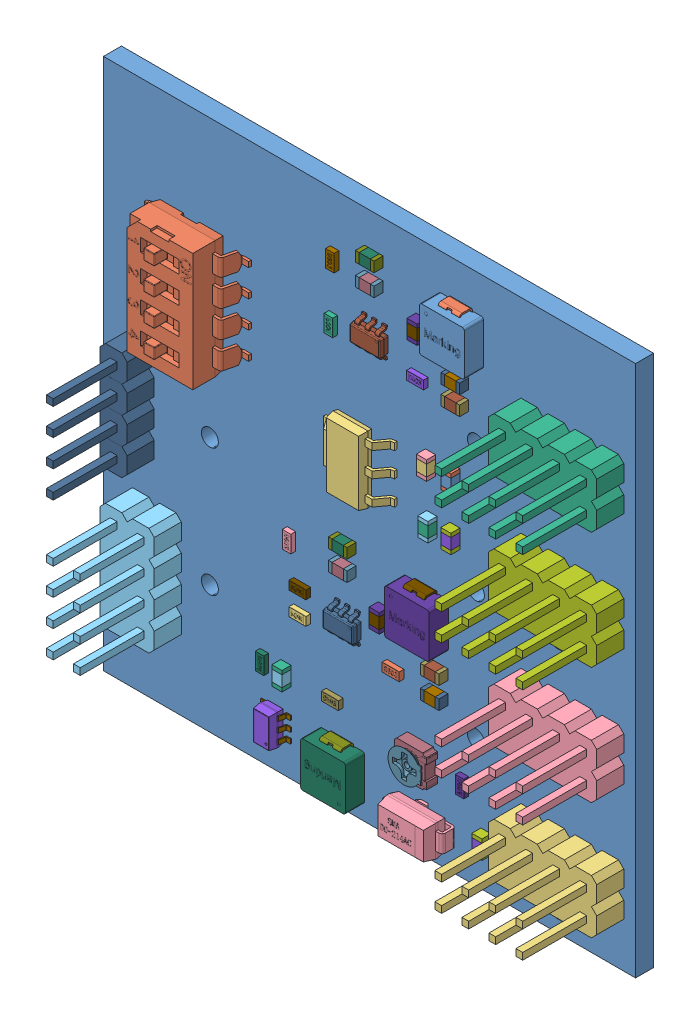
SolidWorks assembly PCB1, configuration 默认. Lengths in mm.
Overall size (50 50 11.54).
196 component instances, 72 part files, 0 mates.
Components (placement in the parent):
- PCB1(2)^PCB1-1: PCB1(2)^PCB1 [默认] at origin size (50 50 11.54) (virtual)
  - Boardbat^PCB1(2)_PCB1-1: Boardbat^PCB1(2)_PCB1 [默认] at origin size (50 50 1.69) (virtual)
    - Open CASCADE STEP translator 6.8 2.1.1^Boardbat_PCB1(2)_PCB1-1: Open CASCADE STEP translator 6.8 2.1.1^Boardbat_PCB1(2)_PCB1 [默认] at (0 0 -1.6914) size (50 50 1.69) (virtual)
  - S1bat^PCB1(2)_PCB1-1: S1bat^PCB1(2)_PCB1 [默认] at origin size (9.8 11.1 4.34) (virtual)
    - SMD_DIP_SWITCH_4P^S1bat_PCB1(2)_PCB1-1: SMD_DIP_SWITCH_4P^S1bat_PCB1(2)_PCB1 [默认] at (9.0244 36.3424 0) x (0 -1 0) z (0 0 1) size (11.1 9.8 4.34) (virtual)
  - P6bat^PCB1(2)_PCB1-1: P6bat^PCB1(2)_PCB1 [默认] at origin size (10.16 5.08 11.54) (virtual)
    - HDR2x4^P6bat_PCB1(2)_PCB1-1: HDR2x4^P6bat_PCB1(2)_PCB1 [默认] at (40.0001 7.5401 0) x (1 0 0) z (0 0 1) size (10.16 5.08 11.54) (virtual)
  - P5bat^PCB1(2)_PCB1-1: P5bat^PCB1(2)_PCB1 [默认] at origin size (10.16 5.08 11.54) (virtual)
    - HDR2x4^P5bat_PCB1(2)_PCB1-1: HDR2x4^P5bat_PCB1(2)_PCB1 [默认] at (40.0001 18.5401 0) x (1 0 0) z (0 0 1) size (10.16 5.08 11.54) (virtual)
  - P4bat^PCB1(2)_PCB1-1: P4bat^PCB1(2)_PCB1 [默认] at origin size (5.08 10.16 11.54) (virtual)
    - HDR2x4^P4bat_PCB1(2)_PCB1-1: HDR2x4^P4bat_PCB1(2)_PCB1 [默认] at (6.0401 14.9999 0) x (0 -1 0) z (0 0 1) size (10.16 5.08 11.54) (virtual)
  - P3bat^PCB1(2)_PCB1-1: P3bat^PCB1(2)_PCB1 [默认] at origin size (10.16 5.08 11.54) (virtual)
    - HDR2x4^P3bat_PCB1(2)_PCB1-1: HDR2x4^P3bat_PCB1(2)_PCB1 [默认] at (40.0001 40.5401 0) x (1 0 0) z (0 0 1) size (10.16 5.08 11.54) (virtual)
  - P2bat^PCB1(2)_PCB1-1: P2bat^PCB1(2)_PCB1 [默认] at origin size (10.16 5.08 11.54) (virtual)
    - HDR2x4^P2bat_PCB1(2)_PCB1-1: HDR2x4^P2bat_PCB1(2)_PCB1 [默认] at (40.0001 29.5401 0) x (1 0 0) z (0 0 1) size (10.16 5.08 11.54) (virtual)
  - U3bat^PCB1(2)_PCB1-1: U3bat^PCB1(2)_PCB1 [默认] at origin size (2.8 2.9 1.45) (virtual)
    - 6249525824^U3bat_PCB1(2)_PCB1-1: 6249525824^U3bat_PCB1(2)_PCB1 [默认] at (16.256 4.064 0) x (-1 0 0) z (0 0 1) size (2.8 2.9 1.45) (virtual)
      - Body^6249525824_U3bat_PCB1(2)_PCB1-1: Body^6249525824_U3bat_PCB1(2)_PCB1 [默认] at origin size (1.6 2.9 1.38) (virtual)
      - PinsArrayLR^6249525824_U3bat_PCB1(2)_PCB1-1: PinsArrayLR^6249525824_U3bat_PCB1(2)_PCB1 [默认] at origin size (2.8 2.3 0.75) (virtual)
  - U2bat^PCB1(2)_PCB1-1: U2bat^PCB1(2)_PCB1 [默认] at origin size (2.9 2.8 1) (virtual)
    - 6249527824^U2bat_PCB1(2)_PCB1-1: 6249527824^U2bat_PCB1(2)_PCB1 [默认] at (22.987 15.509 0) x (0 -1 0) z (-1 0 0) size (2.8 1 2.9) (virtual)
  - U1bat^PCB1(2)_PCB1-1: U1bat^PCB1(2)_PCB1 [默认] at origin size (2.9 2.8 1) (virtual)
    - 6249527824^U1bat_PCB1(2)_PCB1-1: 6249527824^U1bat_PCB1(2)_PCB1 [默认] at (25.527 40.075 0) x (0 -1 0) z (-1 0 0) size (2.8 1 2.9) (virtual)
  - R15bat^PCB1(2)_PCB1-1: R15bat^PCB1(2)_PCB1 [默认] at origin size (1.6 0.8 0.45) (virtual)
    - R0603^R15bat_PCB1(2)_PCB1-1: R0603^R15bat_PCB1(2)_PCB1 [默认] at (21.7171 8.6361 0) x (1 0 0) z (0 0 1) size (1.6 0.8 0.45) (virtual)
  - R14bat^PCB1(2)_PCB1-1: R14bat^PCB1(2)_PCB1 [默认] at origin size (3.46 3.05 1.58) (virtual)
    - 6249526064^R14bat_PCB1(2)_PCB1-1: 6249526064^R14bat_PCB1(2)_PCB1 [默认] at (29.718 7.62 4.4704) x (0 -1 0) z (0 0 -1) size (3.05 3.46 1.58) (virtual)
      - pot1.1^6249526064_R14bat_PCB1(2)_PCB1-1: pot1.1^6249526064_R14bat_PCB1(2)_PCB1 [默认] at (-1.7102 -1.6618 3.4563) size (3 3.46 1.06) (virtual)
      - pot.2^6249526064_R14bat_PCB1(2)_PCB1-1: pot.2^6249526064_R14bat_PCB1(2)_PCB1 [默认] at (-0.2427 -0.0677 2.935) x (-0.009438 0.999936 -0.006241) z (-0.002294 0.00622 0.999978) size (3.06 3 0.7) (virtual)
  - R13bat^PCB1(2)_PCB1-1: R13bat^PCB1(2)_PCB1 [默认] at origin size (0.8 1.6 0.45) (virtual)
    - R0603^R13bat_PCB1(2)_PCB1-1: R0603^R13bat_PCB1(2)_PCB1 [默认] at (15.1131 8.3819 0) x (0 -1 0) z (0 0 1) size (1.6 0.8 0.45) (virtual)
  - R12bat^PCB1(2)_PCB1-1: R12bat^PCB1(2)_PCB1 [默认] at origin size (1.6 0.8 0.45) (virtual)
    - R0603^R12bat_PCB1(2)_PCB1-1: R0603^R12bat_PCB1(2)_PCB1 [默认] at (42.0369 2.4131 -1.6914) x (-1 0 0) z (0 0 -1) size (1.6 0.8 0.45) (virtual)
  - R11bat^PCB1(2)_PCB1-1: R11bat^PCB1(2)_PCB1 [默认] at origin size (0.8 1.6 0.45) (virtual)
    - R0603^R11bat_PCB1(2)_PCB1-1: R0603^R11bat_PCB1(2)_PCB1 [默认] at (33.9091 7.7469 0) x (0 -1 0) z (0 0 1) size (1.6 0.8 0.45) (virtual)
  - R10bat^PCB1(2)_PCB1-1: R10bat^PCB1(2)_PCB1 [默认] at origin size (1.6 0.8 0.45) (virtual)
    - R0603^R10bat_PCB1(2)_PCB1-1: R0603^R10bat_PCB1(2)_PCB1 [默认] at (18.6689 16.1289 0) x (-1 0 0) z (0 0 1) size (1.6 0.8 0.45) (virtual)
  - R9bat^PCB1(2)_PCB1-1: R9bat^PCB1(2)_PCB1 [默认] at origin size (1.6 0.8 0.45) (virtual)
    - R0603^R9bat_PCB1(2)_PCB1-1: R0603^R9bat_PCB1(2)_PCB1 [默认] at (42.0369 13.4621 -1.6914) x (-1 0 0) z (0 0 -1) size (1.6 0.8 0.45) (virtual)
  - R8bat^PCB1(2)_PCB1-1: R8bat^PCB1(2)_PCB1 [默认] at origin size (1.6 0.8 0.45) (virtual)
    - R0603^R8bat_PCB1(2)_PCB1-1: R0603^R8bat_PCB1(2)_PCB1 [默认] at (27.4321 13.8431 0) x (1 0 0) z (0 0 1) size (1.6 0.8 0.45) (virtual)
  - R7bat^PCB1(2)_PCB1-1: R7bat^PCB1(2)_PCB1 [默认] at origin size (1.6 0.8 0.45) (virtual)
    - R0603^R7bat_PCB1(2)_PCB1-1: R0603^R7bat_PCB1(2)_PCB1 [默认] at (18.6689 13.9699 0) x (-1 0 0) z (0 0 1) size (1.6 0.8 0.45) (virtual)
  - R6bat^PCB1(2)_PCB1-1: R6bat^PCB1(2)_PCB1 [默认] at origin size (0.8 1.6 0.45) (virtual)
    - R0603^R6bat_PCB1(2)_PCB1-1: R0603^R6bat_PCB1(2)_PCB1 [默认] at (17.6531 19.5579 0) x (0 -1 0) z (0 0 1) size (1.6 0.8 0.45) (virtual)
  - R5bat^PCB1(2)_PCB1-1: R5bat^PCB1(2)_PCB1 [默认] at origin size (1.6 0.8 0.45) (virtual)
    - R0603^R5bat_PCB1(2)_PCB1-1: R0603^R5bat_PCB1(2)_PCB1 [默认] at (42.0371 24.3839 -1.6914) x (1 0 0) z (0 0 -1) size (1.6 0.8 0.45) (virtual)
  - R4bat^PCB1(2)_PCB1-1: R4bat^PCB1(2)_PCB1 [默认] at origin size (0.8 1.6 0.45) (virtual)
    - R0603^R4bat_PCB1(2)_PCB1-1: R0603^R4bat_PCB1(2)_PCB1 [默认] at (21.5899 39.1161 0) x (0 1 0) z (0 0 1) size (1.6 0.8 0.45) (virtual)
  - R3bat^PCB1(2)_PCB1-1: R3bat^PCB1(2)_PCB1 [默认] at origin size (1.6 0.8 0.45) (virtual)
    - R0603^R3bat_PCB1(2)_PCB1-1: R0603^R3bat_PCB1(2)_PCB1 [默认] at (41.9099 35.4331 -1.6914) x (-1 0 0) z (0 0 -1) size (1.6 0.8 0.45) (virtual)
  - R2bat^PCB1(2)_PCB1-1: R2bat^PCB1(2)_PCB1 [默认] at origin size (1.6 0.8 0.45) (virtual)
    - R0603^R2bat_PCB1(2)_PCB1-1: R0603^R2bat_PCB1(2)_PCB1 [默认] at (29.7181 38.7351 0) x (1 0 0) z (0 0 1) size (1.6 0.8 0.45) (virtual)
  - R1bat^PCB1(2)_PCB1-1: R1bat^PCB1(2)_PCB1 [默认] at origin size (0.8 1.6 0.45) (virtual)
    - R0603^R1bat_PCB1(2)_PCB1-1: R0603^R1bat_PCB1(2)_PCB1 [默认] at (21.7171 44.4499 0) x (0 -1 0) z (0 0 1) size (1.6 0.8 0.45) (virtual)
  - P1bat^PCB1(2)_PCB1-1: P1bat^PCB1(2)_PCB1 [默认] at origin size (2.54 10.16 11.54) (virtual)
    - 1001-4^P1bat_PCB1(2)_PCB1-1: 1001-4^P1bat_PCB1(2)_PCB1 [默认] at (3.5001 27.9999 0) x (0 -1 0) z (0 0 1) size (10.16 2.54 11.54) (virtual)
  - LED4bat^PCB1(2)_PCB1-1: LED4bat^PCB1(2)_PCB1 [默认] at origin size (1.8 0.9 0.8) (virtual)
    - LEDC0603^LED4bat_PCB1(2)_PCB1-1: LEDC0603^LED4bat_PCB1(2)_PCB1 [默认] at (43.9422 2.4131 0) x (1 0 0) z (0 0 1) size (1.8 0.9 0.8) (virtual)
  - LED3bat^PCB1(2)_PCB1-1: LED3bat^PCB1(2)_PCB1 [默认] at origin size (1.8 0.9 0.8) (virtual)
    - LEDC0603^LED3bat_PCB1(2)_PCB1-1: LEDC0603^LED3bat_PCB1(2)_PCB1 [默认] at (43.9422 13.4621 0) x (1 0 0) z (0 0 1) size (1.8 0.9 0.8) (virtual)
  - LED2bat^PCB1(2)_PCB1-1: LED2bat^PCB1(2)_PCB1 [默认] at origin size (1.8 0.9 0.8) (virtual)
    - LEDC0603^LED2bat_PCB1(2)_PCB1-1: LEDC0603^LED2bat_PCB1(2)_PCB1 [默认] at (43.8152 35.4331 0) x (1 0 0) z (0 0 1) size (1.8 0.9 0.8) (virtual)
  - LED1bat^PCB1(2)_PCB1-1: LED1bat^PCB1(2)_PCB1 [默认] at origin size (1.8 0.9 0.8) (virtual)
    - LEDC0603^LED1bat_PCB1(2)_PCB1-1: LEDC0603^LED1bat_PCB1(2)_PCB1 [默认] at (43.9422 24.3841 0) x (1 0 0) z (0 0 1) size (1.8 0.9 0.8) (virtual)
  - L3bat^PCB1(2)_PCB1-1: L3bat^PCB1(2)_PCB1 [默认] at origin size (4.2 4.7 1.85) (virtual)
    - CSAB0420^L3bat_PCB1(2)_PCB1-1: CSAB0420^L3bat_PCB1(2)_PCB1 [默认] at (22.479 3.5744 0.05) x (1 0 0) z (0 0 1) size (4.2 4.7 1.85) (virtual)
      - CSAB0420-0^CSAB0420_L3bat_PCB1(2)_PCB1-1: CSAB0420-0^CSAB0420_L3bat_PCB1(2)_PCB1 [默认] x (1 0 0) z (0 0 -1) size (4.2 4.2 1.8) (virtual)
      - 0420____^CSAB0420_L3bat_PCB1(2)_PCB1-1: 0420____^CSAB0420_L3bat_PCB1(2)_PCB1 [默认] at (0 -2.1 0.425) x (1 0 0) z (0 -1 0) size (2 1.2 0.95) (virtual)
      - 0420____^CSAB0420_L3bat_PCB1(2)_PCB1-2: 0420____^CSAB0420_L3bat_PCB1(2)_PCB1 [默认] at (0 2.1 0.425) x (-1 0 0) z (0 1 0) size (2 1.2 0.95) (virtual)
  - L2bat^PCB1(2)_PCB1-1: L2bat^PCB1(2)_PCB1 [默认] at origin size (4.2 4.7 1.85) (virtual)
    - CSAB0420^L2bat_PCB1(2)_PCB1-1: CSAB0420^L2bat_PCB1(2)_PCB1 [默认] at (30.353 19.9206 0.05) x (-1 0 0) z (0 0 1) size (4.2 4.7 1.85) (virtual)
      - CSAB0420-0^CSAB0420_L2bat_PCB1(2)_PCB1-1: CSAB0420-0^CSAB0420_L2bat_PCB1(2)_PCB1 [默认] x (1 0 0) z (0 0 -1) size (4.2 4.2 1.8) (virtual)
      - 0420____^CSAB0420_L2bat_PCB1(2)_PCB1-1: 0420____^CSAB0420_L2bat_PCB1(2)_PCB1 [默认] at (0 -2.1 0.425) x (1 0 0) z (0 -1 0) size (2 1.2 0.95) (virtual)
      - 0420____^CSAB0420_L2bat_PCB1(2)_PCB1-2: 0420____^CSAB0420_L2bat_PCB1(2)_PCB1 [默认] at (0 2.1 0.425) x (-1 0 0) z (0 1 0) size (2 1.2 0.95) (virtual)
  - L1bat^PCB1(2)_PCB1-1: L1bat^PCB1(2)_PCB1 [默认] at origin size (4.2 4.7 1.85) (virtual)
    - CSAB0420^L1bat_PCB1(2)_PCB1-1: CSAB0420^L1bat_PCB1(2)_PCB1 [默认] at (33.655 44.5586 0.05) x (-1 0 0) z (0 0 1) size (4.2 4.7 1.85) (virtual)
      - CSAB0420-0^CSAB0420_L1bat_PCB1(2)_PCB1-1: CSAB0420-0^CSAB0420_L1bat_PCB1(2)_PCB1 [默认] x (1 0 0) z (0 0 -1) size (4.2 4.2 1.8) (virtual)
      - 0420____^CSAB0420_L1bat_PCB1(2)_PCB1-1: 0420____^CSAB0420_L1bat_PCB1(2)_PCB1 [默认] at (0 -2.1 0.425) x (1 0 0) z (0 -1 0) size (2 1.2 0.95) (virtual)
      - 0420____^CSAB0420_L1bat_PCB1(2)_PCB1-2: 0420____^CSAB0420_L1bat_PCB1(2)_PCB1 [默认] at (0 2.1 0.425) x (-1 0 0) z (0 1 0) size (2 1.2 0.95) (virtual)
  - IC1bat^PCB1(2)_PCB1-1: IC1bat^PCB1(2)_PCB1 [默认] at origin size (6.71 6.3 1.8) (virtual)
    - 6249526864^IC1bat_PCB1(2)_PCB1-1: 6249526864^IC1bat_PCB1(2)_PCB1 [默认] at (24.257 29.845 1.22) x (0 1 0) z (1 0 0) size (6.3 1.8 6.71) (virtual)
  - D1bat^PCB1(2)_PCB1-1: D1bat^PCB1(2)_PCB1 [默认] at origin size (5.81 2.92 2.3) (virtual)
    - SMA(DO-214AC)^D1bat_PCB1(2)_PCB1-1: SMA(DO-214AC)^D1bat_PCB1(2)_PCB1 [默认] at (30.2261 3.0481 0) x (1 0 0) z (0 0 1) size (5.81 2.92 2.3) (virtual)
  - C16bat^PCB1(2)_PCB1-1: C16bat^PCB1(2)_PCB1 [默认] at origin size (0.95 1.75 0.85) (virtual)
    - 6351899600^C16bat_PCB1(2)_PCB1-1: 6351899600^C16bat_PCB1(2)_PCB1 [默认] at (17.145 8.382 0) size (0.95 1.05 0.85) (virtual)
      - Extruded^6351899600_C16bat_PCB1(2)_PCB1-1: Extruded^6351899600_C16bat_PCB1(2)_PCB1 [默认] at origin size (0.95 1.05 0.85) (virtual)
    - 6351899200^C16bat_PCB1(2)_PCB1-1: 6351899200^C16bat_PCB1(2)_PCB1 [默认] at (17.145 9.082 0) size (0.95 0.35 0.85) (virtual)
      - Extruded-1^6351899200_C16bat_PCB1(2)_PCB1-1: Extruded-1^6351899200_C16bat_PCB1(2)_PCB1 [默认] at origin size (0.95 0.35 0.85) (virtual)
    - 6351899200^C16bat_PCB1(2)_PCB1-2: 6351899200^C16bat_PCB1(2)_PCB1 [默认] at (17.145 7.682 0) size (0.95 0.35 0.85) (virtual)
      - Extruded-1^6351899200_C16bat_PCB1(2)_PCB1-1: Extruded-1^6351899200_C16bat_PCB1(2)_PCB1 [默认] at origin size (0.95 0.35 0.85) (virtual)
  - C15bat^PCB1(2)_PCB1-1: C15bat^PCB1(2)_PCB1 [默认] at origin size (0.95 1.75 0.85) (virtual)
    - 6351899200^C15bat_PCB1(2)_PCB1-1: 6351899200^C15bat_PCB1(2)_PCB1 [默认] at (35.941 4.764 0) size (0.95 0.35 0.85) (virtual)
      - Extruded-1^6351899200_C15bat_PCB1(2)_PCB1-1: Extruded-1^6351899200_C15bat_PCB1(2)_PCB1 [默认] at origin size (0.95 0.35 0.85) (virtual)
    - 6351899200^C15bat_PCB1(2)_PCB1-2: 6351899200^C15bat_PCB1(2)_PCB1 [默认] at (35.941 3.364 0) size (0.95 0.35 0.85) (virtual)
      - Extruded-1^6351899200_C15bat_PCB1(2)_PCB1-1: Extruded-1^6351899200_C15bat_PCB1(2)_PCB1 [默认] at origin size (0.95 0.35 0.85) (virtual)
    - 6351899600^C15bat_PCB1(2)_PCB1-1: 6351899600^C15bat_PCB1(2)_PCB1 [默认] at (35.941 4.064 0) size (0.95 1.05 0.85) (virtual)
      - Extruded^6351899600_C15bat_PCB1(2)_PCB1-1: Extruded^6351899600_C15bat_PCB1(2)_PCB1 [默认] at origin size (0.95 1.05 0.85) (virtual)
  - C14bat^PCB1(2)_PCB1-1: C14bat^PCB1(2)_PCB1 [默认] at origin size (1.75 0.95 0.85) (virtual)
    - 6351616128^C14bat_PCB1(2)_PCB1-1: 6351616128^C14bat_PCB1(2)_PCB1 [默认] at (31.496 13.843 0) size (1.05 0.95 0.85) (virtual)
      - Extruded-2^6351616128_C14bat_PCB1(2)_PCB1-1: Extruded-2^6351616128_C14bat_PCB1(2)_PCB1 [默认] at origin size (1.05 0.95 0.85) (virtual)
    - 6351615888^C14bat_PCB1(2)_PCB1-1: 6351615888^C14bat_PCB1(2)_PCB1 [默认] at (32.196 13.843 0) size (0.35 0.95 0.85) (virtual)
      - Extruded-3^6351615888_C14bat_PCB1(2)_PCB1-1: Extruded-3^6351615888_C14bat_PCB1(2)_PCB1 [默认] at origin size (0.35 0.95 0.85) (virtual)
    - 6351615888^C14bat_PCB1(2)_PCB1-2: 6351615888^C14bat_PCB1(2)_PCB1 [默认] at (30.796 13.843 0) size (0.35 0.95 0.85) (virtual)
      - Extruded-3^6351615888_C14bat_PCB1(2)_PCB1-1: Extruded-3^6351615888_C14bat_PCB1(2)_PCB1 [默认] at origin size (0.35 0.95 0.85) (virtual)
  - C13bat^PCB1(2)_PCB1-1: C13bat^PCB1(2)_PCB1 [默认] at origin size (1.75 0.95 0.85) (virtual)
    - 6351616128^C13bat_PCB1(2)_PCB1-1: 6351616128^C13bat_PCB1(2)_PCB1 [默认] at (31.496 15.875 0) size (1.05 0.95 0.85) (virtual)
      - Extruded-2^6351616128_C13bat_PCB1(2)_PCB1-1: Extruded-2^6351616128_C13bat_PCB1(2)_PCB1 [默认] at origin size (1.05 0.95 0.85) (virtual)
    - 6351615888^C13bat_PCB1(2)_PCB1-1: 6351615888^C13bat_PCB1(2)_PCB1 [默认] at (32.196 15.875 0) size (0.35 0.95 0.85) (virtual)
      - Extruded-3^6351615888_C13bat_PCB1(2)_PCB1-1: Extruded-3^6351615888_C13bat_PCB1(2)_PCB1 [默认] at origin size (0.35 0.95 0.85) (virtual)
    - 6351615888^C13bat_PCB1(2)_PCB1-2: 6351615888^C13bat_PCB1(2)_PCB1 [默认] at (30.796 15.875 0) size (0.35 0.95 0.85) (virtual)
      - Extruded-3^6351615888_C13bat_PCB1(2)_PCB1-1: Extruded-3^6351615888_C13bat_PCB1(2)_PCB1 [默认] at origin size (0.35 0.95 0.85) (virtual)
  - C12bat^PCB1(2)_PCB1-1: C12bat^PCB1(2)_PCB1 [默认] at origin size (1.75 0.95 0.85) (virtual)
    - 6351616128^C12bat_PCB1(2)_PCB1-1: 6351616128^C12bat_PCB1(2)_PCB1 [默认] at (22.86 19.939 0) size (1.05 0.95 0.85) (virtual)
      - Extruded-2^6351616128_C12bat_PCB1(2)_PCB1-1: Extruded-2^6351616128_C12bat_PCB1(2)_PCB1 [默认] at origin size (1.05 0.95 0.85) (virtual)
    - 6351615888^C12bat_PCB1(2)_PCB1-1: 6351615888^C12bat_PCB1(2)_PCB1 [默认] at (22.16 19.939 0) size (0.35 0.95 0.85) (virtual)
      - Extruded-3^6351615888_C12bat_PCB1(2)_PCB1-1: Extruded-3^6351615888_C12bat_PCB1(2)_PCB1 [默认] at origin size (0.35 0.95 0.85) (virtual)
    - 6351615888^C12bat_PCB1(2)_PCB1-2: 6351615888^C12bat_PCB1(2)_PCB1 [默认] at (23.56 19.939 0) size (0.35 0.95 0.85) (virtual)
      - Extruded-3^6351615888_C12bat_PCB1(2)_PCB1-1: Extruded-3^6351615888_C12bat_PCB1(2)_PCB1 [默认] at origin size (0.35 0.95 0.85) (virtual)
  - C11bat^PCB1(2)_PCB1-1: C11bat^PCB1(2)_PCB1 [默认] at origin size (1.75 0.95 0.85) (virtual)
    - 6351616128^C11bat_PCB1(2)_PCB1-1: 6351616128^C11bat_PCB1(2)_PCB1 [默认] at (22.86 21.844 0) size (1.05 0.95 0.85) (virtual)
      - Extruded-2^6351616128_C11bat_PCB1(2)_PCB1-1: Extruded-2^6351616128_C11bat_PCB1(2)_PCB1 [默认] at origin size (1.05 0.95 0.85) (virtual)
    - 6351615888^C11bat_PCB1(2)_PCB1-1: 6351615888^C11bat_PCB1(2)_PCB1 [默认] at (22.16 21.844 0) size (0.35 0.95 0.85) (virtual)
      - Extruded-3^6351615888_C11bat_PCB1(2)_PCB1-1: Extruded-3^6351615888_C11bat_PCB1(2)_PCB1 [默认] at origin size (0.35 0.95 0.85) (virtual)
    - 6351615888^C11bat_PCB1(2)_PCB1-2: 6351615888^C11bat_PCB1(2)_PCB1 [默认] at (23.56 21.844 0) size (0.35 0.95 0.85) (virtual)
      - Extruded-3^6351615888_C11bat_PCB1(2)_PCB1-1: Extruded-3^6351615888_C11bat_PCB1(2)_PCB1 [默认] at origin size (0.35 0.95 0.85) (virtual)
  - C10bat^PCB1(2)_PCB1-1: C10bat^PCB1(2)_PCB1 [默认] at origin size (0.95 1.75 0.85) (virtual)
    - 6351899200^C10bat_PCB1(2)_PCB1-1: 6351899200^C10bat_PCB1(2)_PCB1 [默认] at (26.289 18.353 0) size (0.95 0.35 0.85) (virtual)
      - Extruded-1^6351899200_C10bat_PCB1(2)_PCB1-1: Extruded-1^6351899200_C10bat_PCB1(2)_PCB1 [默认] at origin size (0.95 0.35 0.85) (virtual)
    - 6351899200^C10bat_PCB1(2)_PCB1-2: 6351899200^C10bat_PCB1(2)_PCB1 [默认] at (26.289 16.953 0) size (0.95 0.35 0.85) (virtual)
      - Extruded-1^6351899200_C10bat_PCB1(2)_PCB1-1: Extruded-1^6351899200_C10bat_PCB1(2)_PCB1 [默认] at origin size (0.95 0.35 0.85) (virtual)
    - 6351899600^C10bat_PCB1(2)_PCB1-1: 6351899600^C10bat_PCB1(2)_PCB1 [默认] at (26.289 17.653 0) size (0.95 1.05 0.85) (virtual)
      - Extruded^6351899600_C10bat_PCB1(2)_PCB1-1: Extruded^6351899600_C10bat_PCB1(2)_PCB1 [默认] at origin size (0.95 1.05 0.85) (virtual)
  - C9bat^PCB1(2)_PCB1-1: C9bat^PCB1(2)_PCB1 [默认] at origin size (0.95 1.75 0.85) (virtual)
    - 6351899600^C9bat_PCB1(2)_PCB1-1: 6351899600^C9bat_PCB1(2)_PCB1 [默认] at (33.02 32.315 0) size (0.95 1.05 0.85) (virtual)
      - Extruded^6351899600_C9bat_PCB1(2)_PCB1-1: Extruded^6351899600_C9bat_PCB1(2)_PCB1 [默认] at origin size (0.95 1.05 0.85) (virtual)
    - 6351899200^C9bat_PCB1(2)_PCB1-1: 6351899200^C9bat_PCB1(2)_PCB1 [默认] at (33.02 31.615 0) size (0.95 0.35 0.85) (virtual)
      - Extruded-1^6351899200_C9bat_PCB1(2)_PCB1-1: Extruded-1^6351899200_C9bat_PCB1(2)_PCB1 [默认] at origin size (0.95 0.35 0.85) (virtual)
    - 6351899200^C9bat_PCB1(2)_PCB1-2: 6351899200^C9bat_PCB1(2)_PCB1 [默认] at (33.02 33.015 0) size (0.95 0.35 0.85) (virtual)
      - Extruded-1^6351899200_C9bat_PCB1(2)_PCB1-1: Extruded-1^6351899200_C9bat_PCB1(2)_PCB1 [默认] at origin size (0.95 0.35 0.85) (virtual)
  - C8bat^PCB1(2)_PCB1-1: C8bat^PCB1(2)_PCB1 [默认] at origin size (0.95 1.75 0.85) (virtual)
    - 6351899600^C8bat_PCB1(2)_PCB1-1: 6351899600^C8bat_PCB1(2)_PCB1 [默认] at (30.734 32.315 0) size (0.95 1.05 0.85) (virtual)
      - Extruded^6351899600_C8bat_PCB1(2)_PCB1-1: Extruded^6351899600_C8bat_PCB1(2)_PCB1 [默认] at origin size (0.95 1.05 0.85) (virtual)
    - 6351899200^C8bat_PCB1(2)_PCB1-1: 6351899200^C8bat_PCB1(2)_PCB1 [默认] at (30.734 31.615 0) size (0.95 0.35 0.85) (virtual)
      - Extruded-1^6351899200_C8bat_PCB1(2)_PCB1-1: Extruded-1^6351899200_C8bat_PCB1(2)_PCB1 [默认] at origin size (0.95 0.35 0.85) (virtual)
    - 6351899200^C8bat_PCB1(2)_PCB1-2: 6351899200^C8bat_PCB1(2)_PCB1 [默认] at (30.734 33.015 0) size (0.95 0.35 0.85) (virtual)
      - Extruded-1^6351899200_C8bat_PCB1(2)_PCB1-1: Extruded-1^6351899200_C8bat_PCB1(2)_PCB1 [默认] at origin size (0.95 0.35 0.85) (virtual)
  - C7bat^PCB1(2)_PCB1-1: C7bat^PCB1(2)_PCB1 [默认] at origin size (0.95 1.75 0.85) (virtual)
    - 6351899200^C7bat_PCB1(2)_PCB1-1: 6351899200^C7bat_PCB1(2)_PCB1 [默认] at (30.861 28.062 0) size (0.95 0.35 0.85) (virtual)
      - Extruded-1^6351899200_C7bat_PCB1(2)_PCB1-1: Extruded-1^6351899200_C7bat_PCB1(2)_PCB1 [默认] at origin size (0.95 0.35 0.85) (virtual)
    - 6351899200^C7bat_PCB1(2)_PCB1-2: 6351899200^C7bat_PCB1(2)_PCB1 [默认] at (30.861 26.662 0) size (0.95 0.35 0.85) (virtual)
      - Extruded-1^6351899200_C7bat_PCB1(2)_PCB1-1: Extruded-1^6351899200_C7bat_PCB1(2)_PCB1 [默认] at origin size (0.95 0.35 0.85) (virtual)
    - 6351899600^C7bat_PCB1(2)_PCB1-1: 6351899600^C7bat_PCB1(2)_PCB1 [默认] at (30.861 27.362 0) size (0.95 1.05 0.85) (virtual)
      - Extruded^6351899600_C7bat_PCB1(2)_PCB1-1: Extruded^6351899600_C7bat_PCB1(2)_PCB1 [默认] at origin size (0.95 1.05 0.85) (virtual)
  - C6bat^PCB1(2)_PCB1-1: C6bat^PCB1(2)_PCB1 [默认] at origin size (0.95 1.75 0.85) (virtual)
    - 6351899200^C6bat_PCB1(2)_PCB1-1: 6351899200^C6bat_PCB1(2)_PCB1 [默认] at (33.02 28.189 0) size (0.95 0.35 0.85) (virtual)
      - Extruded-1^6351899200_C6bat_PCB1(2)_PCB1-1: Extruded-1^6351899200_C6bat_PCB1(2)_PCB1 [默认] at origin size (0.95 0.35 0.85) (virtual)
    - 6351899200^C6bat_PCB1(2)_PCB1-2: 6351899200^C6bat_PCB1(2)_PCB1 [默认] at (33.02 26.789 0) size (0.95 0.35 0.85) (virtual)
      - Extruded-1^6351899200_C6bat_PCB1(2)_PCB1-1: Extruded-1^6351899200_C6bat_PCB1(2)_PCB1 [默认] at origin size (0.95 0.35 0.85) (virtual)
    - 6351899600^C6bat_PCB1(2)_PCB1-1: 6351899600^C6bat_PCB1(2)_PCB1 [默认] at (33.02 27.489 0) size (0.95 1.05 0.85) (virtual)
      - Extruded^6351899600_C6bat_PCB1(2)_PCB1-1: Extruded^6351899600_C6bat_PCB1(2)_PCB1 [默认] at origin size (0.95 1.05 0.85) (virtual)
  - C5bat^PCB1(2)_PCB1-1: C5bat^PCB1(2)_PCB1 [默认] at origin size (1.75 0.95 0.85) (virtual)
    - 6351616128^C5bat_PCB1(2)_PCB1-1: 6351616128^C5bat_PCB1(2)_PCB1 [默认] at (33.44 40.513 0) size (1.05 0.95 0.85) (virtual)
      - Extruded-2^6351616128_C5bat_PCB1(2)_PCB1-1: Extruded-2^6351616128_C5bat_PCB1(2)_PCB1 [默认] at origin size (1.05 0.95 0.85) (virtual)
    - 6351615888^C5bat_PCB1(2)_PCB1-1: 6351615888^C5bat_PCB1(2)_PCB1 [默认] at (34.14 40.513 0) size (0.35 0.95 0.85) (virtual)
      - Extruded-3^6351615888_C5bat_PCB1(2)_PCB1-1: Extruded-3^6351615888_C5bat_PCB1(2)_PCB1 [默认] at origin size (0.35 0.95 0.85) (virtual)
    - 6351615888^C5bat_PCB1(2)_PCB1-2: 6351615888^C5bat_PCB1(2)_PCB1 [默认] at (32.74 40.513 0) size (0.35 0.95 0.85) (virtual)
      - Extruded-3^6351615888_C5bat_PCB1(2)_PCB1-1: Extruded-3^6351615888_C5bat_PCB1(2)_PCB1 [默认] at origin size (0.35 0.95 0.85) (virtual)
  - C4bat^PCB1(2)_PCB1-1: C4bat^PCB1(2)_PCB1 [默认] at origin size (1.75 0.95 0.85) (virtual)
    - 6351616128^C4bat_PCB1(2)_PCB1-1: 6351616128^C4bat_PCB1(2)_PCB1 [默认] at (33.44 38.735 0) size (1.05 0.95 0.85) (virtual)
      - Extruded-2^6351616128_C4bat_PCB1(2)_PCB1-1: Extruded-2^6351616128_C4bat_PCB1(2)_PCB1 [默认] at origin size (1.05 0.95 0.85) (virtual)
    - 6351615888^C4bat_PCB1(2)_PCB1-1: 6351615888^C4bat_PCB1(2)_PCB1 [默认] at (34.14 38.735 0) size (0.35 0.95 0.85) (virtual)
      - Extruded-3^6351615888_C4bat_PCB1(2)_PCB1-1: Extruded-3^6351615888_C4bat_PCB1(2)_PCB1 [默认] at origin size (0.35 0.95 0.85) (virtual)
    - 6351615888^C4bat_PCB1(2)_PCB1-2: 6351615888^C4bat_PCB1(2)_PCB1 [默认] at (32.74 38.735 0) size (0.35 0.95 0.85) (virtual)
      - Extruded-3^6351615888_C4bat_PCB1(2)_PCB1-1: Extruded-3^6351615888_C4bat_PCB1(2)_PCB1 [默认] at origin size (0.35 0.95 0.85) (virtual)
  - C3bat^PCB1(2)_PCB1-1: C3bat^PCB1(2)_PCB1 [默认] at origin size (1.75 0.95 0.85) (virtual)
    - 6351616128^C3bat_PCB1(2)_PCB1-1: 6351616128^C3bat_PCB1(2)_PCB1 [默认] at (25.4 44.393 0) size (1.05 0.95 0.85) (virtual)
      - Extruded-2^6351616128_C3bat_PCB1(2)_PCB1-1: Extruded-2^6351616128_C3bat_PCB1(2)_PCB1 [默认] at origin size (1.05 0.95 0.85) (virtual)
    - 6351615888^C3bat_PCB1(2)_PCB1-1: 6351615888^C3bat_PCB1(2)_PCB1 [默认] at (24.7 44.393 0) size (0.35 0.95 0.85) (virtual)
      - Extruded-3^6351615888_C3bat_PCB1(2)_PCB1-1: Extruded-3^6351615888_C3bat_PCB1(2)_PCB1 [默认] at origin size (0.35 0.95 0.85) (virtual)
    - 6351615888^C3bat_PCB1(2)_PCB1-2: 6351615888^C3bat_PCB1(2)_PCB1 [默认] at (26.1 44.393 0) size (0.35 0.95 0.85) (virtual)
      - Extruded-3^6351615888_C3bat_PCB1(2)_PCB1-1: Extruded-3^6351615888_C3bat_PCB1(2)_PCB1 [默认] at origin size (0.35 0.95 0.85) (virtual)
  - C2bat^PCB1(2)_PCB1-1: C2bat^PCB1(2)_PCB1 [默认] at origin size (1.75 0.95 0.85) (virtual)
    - 6351616128^C2bat_PCB1(2)_PCB1-1: 6351616128^C2bat_PCB1(2)_PCB1 [默认] at (25.4 46.425 0) size (1.05 0.95 0.85) (virtual)
      - Extruded-2^6351616128_C2bat_PCB1(2)_PCB1-1: Extruded-2^6351616128_C2bat_PCB1(2)_PCB1 [默认] at origin size (1.05 0.95 0.85) (virtual)
    - 6351615888^C2bat_PCB1(2)_PCB1-1: 6351615888^C2bat_PCB1(2)_PCB1 [默认] at (24.7 46.425 0) size (0.35 0.95 0.85) (virtual)
      - Extruded-3^6351615888_C2bat_PCB1(2)_PCB1-1: Extruded-3^6351615888_C2bat_PCB1(2)_PCB1 [默认] at origin size (0.35 0.95 0.85) (virtual)
    - 6351615888^C2bat_PCB1(2)_PCB1-2: 6351615888^C2bat_PCB1(2)_PCB1 [默认] at (26.1 46.425 0) size (0.35 0.95 0.85) (virtual)
      - Extruded-3^6351615888_C2bat_PCB1(2)_PCB1-1: Extruded-3^6351615888_C2bat_PCB1(2)_PCB1 [默认] at origin size (0.35 0.95 0.85) (virtual)
  - C1bat^PCB1(2)_PCB1-1: C1bat^PCB1(2)_PCB1 [默认] at origin size (0.95 1.75 0.85) (virtual)
    - 6351899200^C1bat_PCB1(2)_PCB1-1: 6351899200^C1bat_PCB1(2)_PCB1 [默认] at (29.845 43.626 0) size (0.95 0.35 0.85) (virtual)
      - Extruded-1^6351899200_C1bat_PCB1(2)_PCB1-1: Extruded-1^6351899200_C1bat_PCB1(2)_PCB1 [默认] at origin size (0.95 0.35 0.85) (virtual)
    - 6351899200^C1bat_PCB1(2)_PCB1-2: 6351899200^C1bat_PCB1(2)_PCB1 [默认] at (29.845 42.226 0) size (0.95 0.35 0.85) (virtual)
      - Extruded-1^6351899200_C1bat_PCB1(2)_PCB1-1: Extruded-1^6351899200_C1bat_PCB1(2)_PCB1 [默认] at origin size (0.95 0.35 0.85) (virtual)
    - 6351899600^C1bat_PCB1(2)_PCB1-1: 6351899600^C1bat_PCB1(2)_PCB1 [默认] at (29.845 42.926 0) size (0.95 1.05 0.85) (virtual)
      - Extruded^6351899600_C1bat_PCB1(2)_PCB1-1: Extruded^6351899600_C1bat_PCB1(2)_PCB1 [默认] at origin size (0.95 1.05 0.85) (virtual)
